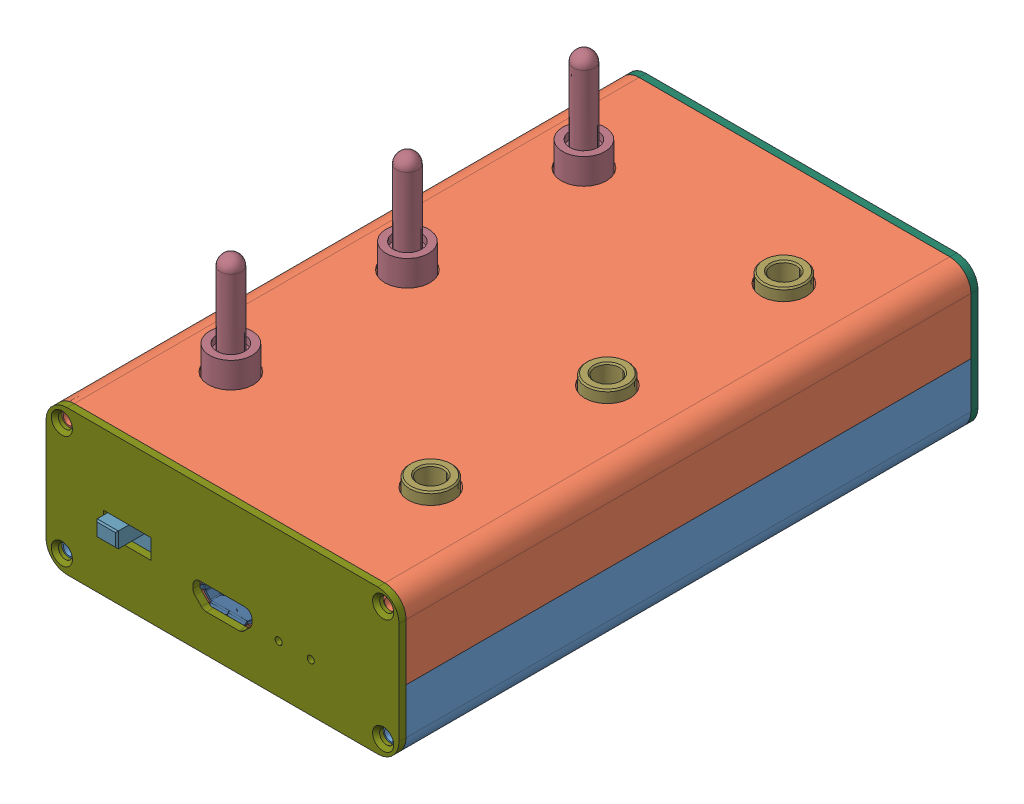
SolidWorks assembly case-full, configuration Default. Lengths in mm.
Overall size (50 35 83.41).
112 component instances, 26 part files, 14 mates.
Components (placement in the parent):
- case-1: case [Default] at (-9.9049 -10.2865 -40) size (50 11 80)
- top-case-2: top-case [Default] at (1.6835 8.41 -40) x (-1 0 0) z (0 0 1) size (50 11 80)
- PCB-assembly-1: PCB-assembly [Default] at (-5.9703 -42.4723 -73.1659) x (0 0 -1) z (0 1 0) size (82.41 47 32.65)
  - ledTruck_PCB.step-1: ledTruck_PCB.step [Default] at (-218.1999 94.1524 35.3841) size (80.38 47 12.68)
    - ledTruck.step-1: ledTruck.step [Default] at origin size (80.38 47 12.68)
      - R_0603_1608Metric.step-1: R_0603_1608Metric.step [Default] at (162.2298 -104.8258 1.65) size (1.6 0.8 0.45)
        - SOLID.step-1: SOLID.step [Default] at origin size (1.6 0.8 0.45)
      - SOT-23-5.step-1: SOT-23-5.step [Default] at (130.302 -76.708 1.65) x (0 -1 0) z (0 0 1) size (2.8 2.9 1.55)
        - SOLID-0.step-1: SOLID-0.step [Default] at origin size (2.8 2.9 1.55)
      - SOT-23-5.step-2: SOT-23-5.step [Default] at (137.16 -76.708 1.65) x (0 -1 0) z (0 0 1) size (2.8 2.9 1.55)
        - SOLID-0.step-1: SOLID-0.step [Default] at origin size (2.8 2.9 1.55)
      - R_0603_1608Metric.step-2: R_0603_1608Metric.step [Default] at (162.433 -79.248 1.65) size (1.6 0.8 0.45)
        - SOLID.step-1: SOLID.step [Default] at origin size (1.6 0.8 0.45)
      - R_0603_1608Metric.step-3: R_0603_1608Metric.step [Default] at (162.433 -76.835 1.65) x (-1 0 0) z (0 0 1) size (1.6 0.8 0.45)
        - SOLID.step-1: SOLID.step [Default] at origin size (1.6 0.8 0.45)
      - R_0603_1608Metric.step-4: R_0603_1608Metric.step [Default] at (108.1929 -114.012 1.65) size (1.6 0.8 0.45)
        - SOLID.step-1: SOLID.step [Default] at origin size (1.6 0.8 0.45)
      - R_0603_1608Metric.step-5: R_0603_1608Metric.step [Default] at (108.1929 -115.512 1.65) size (1.6 0.8 0.45)
        - SOLID.step-1: SOLID.step [Default] at origin size (1.6 0.8 0.45)
      - R_0603_1608Metric.step-6: R_0603_1608Metric.step [Default] at (152.146 -80.01 1.65) size (1.6 0.8 0.45)
        - SOLID.step-1: SOLID.step [Default] at origin size (1.6 0.8 0.45)
      - R_0603_1608Metric.step-7: R_0603_1608Metric.step [Default] at (165.1 -84.836 1.65) x (0 1 0) z (0 0 1) size (1.6 0.8 0.45)
        - SOLID.step-1: SOLID.step [Default] at origin size (1.6 0.8 0.45)
      - R_0603_1608Metric.step-8: R_0603_1608Metric.step [Default] at (137.16 -80.264 1.65) x (-1 0 0) z (0 0 1) size (1.6 0.8 0.45)
        - SOLID.step-1: SOLID.step [Default] at origin size (1.6 0.8 0.45)
      - R_0603_1608Metric.step-9: R_0603_1608Metric.step [Default] at (156.972 -111.506 1.65) x (-1 0 0) z (0 0 1) size (1.6 0.8 0.45)
        - SOLID.step-1: SOLID.step [Default] at origin size (1.6 0.8 0.45)
      - R_0603_1608Metric.step-10: R_0603_1608Metric.step [Default] at (156.972 -107.442 1.65) size (1.6 0.8 0.45)
        - SOLID.step-1: SOLID.step [Default] at origin size (1.6 0.8 0.45)
      - R_0603_1608Metric.step-11: R_0603_1608Metric.step [Default] at (132.842 -113.284 1.65) size (1.6 0.8 0.45)
        - SOLID.step-1: SOLID.step [Default] at origin size (1.6 0.8 0.45)
      - R_0603_1608Metric.step-12: R_0603_1608Metric.step [Default] at (156.972 -109.474 1.65) x (-1 0 0) z (0 0 1) size (1.6 0.8 0.45)
        - SOLID.step-1: SOLID.step [Default] at origin size (1.6 0.8 0.45)
      - R_0603_1608Metric.step-13: R_0603_1608Metric.step [Default] at (156.972 -105.283 1.65) x (-1 0 0) z (0 0 1) size (1.6 0.8 0.45)
        - SOLID.step-1: SOLID.step [Default] at origin size (1.6 0.8 0.45)
      - R_0603_1608Metric.step-14: R_0603_1608Metric.step [Default] at (132.828 -111.379 1.65) size (1.6 0.8 0.45)
        - SOLID.step-1: SOLID.step [Default] at origin size (1.6 0.8 0.45)
      - L_0805_2012Metric.step-1: L_0805_2012Metric.step [Default] at (130.336 -80.264 1.65) x (-1 0 0) z (0 0 1) size (2 1.25 1.25)
        - SOLID-1.step-1: SOLID-1.step [Default] at origin size (2 1.25 1.25)
      - C_0805_2012Metric.step-1: C_0805_2012Metric.step [Default] at (130.302 -87.122 1.65) size (2 1.25 1.25)
        - SOLID-2.step-1: SOLID-2.step [Default] at origin size (2 1.25 1.25)
      - C_0603_1608Metric.step-1: C_0603_1608Metric.step [Default] at (152.146 -78.486 1.65) x (-1 0 0) z (0 0 1) size (1.6 0.8 0.8)
        - SOLID-3.step-1: SOLID-3.step [Default] at origin size (1.6 0.8 0.8)
      - C_0805_2012Metric.step-2: C_0805_2012Metric.step [Default] at (137.16 -83.566 1.65) size (2 1.25 1.25)
        - SOLID-2.step-1: SOLID-2.step [Default] at origin size (2 1.25 1.25)
      - C_0603_1608Metric.step-2: C_0603_1608Metric.step [Default] at (152.146 -76.962 1.65) x (-1 0 0) z (0 0 1) size (1.6 0.8 0.8)
        - SOLID-3.step-1: SOLID-3.step [Default] at origin size (1.6 0.8 0.8)
      - C_0603_1608Metric.step-3: C_0603_1608Metric.step [Default] at (152.146 -75.464 1.65) x (-1 0 0) z (0 0 1) size (1.6 0.8 0.8)
        - SOLID-3.step-1: SOLID-3.step [Default] at origin size (1.6 0.8 0.8)
      - C_0805_2012Metric.step-3: C_0805_2012Metric.step [Default] at (130.302 -83.566 1.65) size (2 1.25 1.25)
        - SOLID-2.step-1: SOLID-2.step [Default] at origin size (2 1.25 1.25)
      - C_0603_1608Metric.step-4: C_0603_1608Metric.step [Default] at (162.56 -81.534 1.65) size (1.6 0.8 0.8)
        - SOLID-3.step-1: SOLID-3.step [Default] at origin size (1.6 0.8 0.8)
      - C_0603_1608Metric.step-5: C_0603_1608Metric.step [Default] at (162.56 -88.138 1.65) size (1.6 0.8 0.8)
        - SOLID-3.step-1: SOLID-3.step [Default] at origin size (1.6 0.8 0.8)
      - C_0805_2012Metric.step-4: C_0805_2012Metric.step [Default] at (137.16 -87.122 1.65) size (2 1.25 1.25)
        - SOLID-2.step-1: SOLID-2.step [Default] at origin size (2 1.25 1.25)
      - R_0603_1608Metric.step-15: R_0603_1608Metric.step [Default] at (125.984 -75.946 1.65) size (1.6 0.8 0.45)
        - SOLID.step-1: SOLID.step [Default] at origin size (1.6 0.8 0.45)
      - R_0603_1608Metric.step-16: R_0603_1608Metric.step [Default] at (114.046 -80.264 1.65) x (0 -1 0) z (0 0 1) size (1.6 0.8 0.45)
        - SOLID.step-1: SOLID.step [Default] at origin size (1.6 0.8 0.45)
      - LED_0805_2012Metric.step-1: LED_0805_2012Metric.step [Default] at (107.6929 -108.512 1.65) x (0 -1 0) z (0 0 1) size (2 1.25 1.1)
        - SOLID-4.step-1: SOLID-4.step [Default] at origin size (2 1.25 1.1)
      - LED_0805_2012Metric.step-2: LED_0805_2012Metric.step [Default] at (107.6929 -103.962 1.65) x (0 -1 0) z (0 0 1) size (2 1.25 1.1)
        - SOLID-4.step-1: SOLID-4.step [Default] at origin size (2 1.25 1.1)
      - C_0603_1608Metric.step-6: C_0603_1608Metric.step [Default] at (125.984 -77.978 1.65) x (-1 0 0) z (0 0 1) size (1.6 0.8 0.8)
        - SOLID-3.step-1: SOLID-3.step [Default] at origin size (1.6 0.8 0.8)
      - SW_CuK_JS202011AQN_DPDT_Angled.step-1: SW_CuK_JS202011AQN_DPDT_Angled.step [Default] at (111.474 -79.012 1.65) x (0 -1 0) z (0 0 1) size (9 5.6 6.5) (hidden)
        - SOLID-5.step-1: SOLID-5.step [Default] at origin size (9 5.6 6.5)
      - JST_XH_S2B-XH-A_1x02_P2.50mm_Horizontal.step-1: JST_XH_S2B-XH-A_1x02_P2.50mm_Horizontal.step [Default] at (179.578 -78.012 1.65) size (7.4 11.5 9.5)
        - SOLID-6.step-1: SOLID-6.step [Default] at origin size (7.4 11.5 9.5)
      - USB_Micro-B_Molex_47346-0001.step-1: USB_Micro-B_Molex_47346-0001.step [Default] at (108.4213 -96.0044 1.65) x (0 -1 0) z (0 0 1) size (7.98 5.42 2.94)
        - SOLID-7.step-1: SOLID-7.step [Default] at origin size (7.98 5.42 2.94)
      - Crystal_SMD_0603-4Pin_6.0x3.5mm.step-1: Crystal_SMD_0603-4Pin_6.0x3.5mm.step [Default] at (162.56 -84.856 1.65) x (0 1 0) z (0 0 1) size (6 3.5 1.03)
        - SOLID-8.step-1: SOLID-8.step [Default] at origin size (6 3.5 1.03) (hidden)
      - 7101 ToggleSwitch.step-1: 7101 ToggleSwitch.step [Default] at (121.534 -82.012 10.15) size (0.36 0.5 1.28) (hidden)
        - SOLID-9.step-1: SOLID-9.step [Default] at origin size (0.28 0.5 0.35) (hidden)
        - SOLID-10.step-1: SOLID-10.step [Default] at origin size (0.24 0.24 0.35)
        - SOLID-11.step-1: SOLID-11.step [Default] at origin size (0.12 0.21 0.43)
        - SOLID-12.step-1: SOLID-12.step [Default] at origin size (0.36 0.31 0.06)
        - SOLID-13.step-1: SOLID-13.step [Default] at origin size (0.36 0.31 0.06)
        - SOLID-14.step-1: SOLID-14.step [Default] at origin size (0.08 0.03 0.16)
        - SOLID-15.step-1: SOLID-15.step [Default] at origin size (0.08 0.03 0.16)
        - SOLID-16.step-1: SOLID-16.step [Default] at origin size (0.08 0.03 0.16)
      - 7101 ToggleSwitch.step-2: 7101 ToggleSwitch.step [Default] at (146.534 -82.012 10.15) size (0.36 0.5 1.28) (hidden)
        - SOLID-9.step-1: SOLID-9.step [Default] at origin size (0.28 0.5 0.35) (hidden)
        - SOLID-10.step-1: SOLID-10.step [Default] at origin size (0.24 0.24 0.35)
        - SOLID-11.step-1: SOLID-11.step [Default] at origin size (0.12 0.21 0.43)
        - SOLID-12.step-1: SOLID-12.step [Default] at origin size (0.36 0.31 0.06)
        - SOLID-13.step-1: SOLID-13.step [Default] at origin size (0.36 0.31 0.06)
        - SOLID-14.step-1: SOLID-14.step [Default] at origin size (0.08 0.03 0.16)
        - SOLID-15.step-1: SOLID-15.step [Default] at origin size (0.08 0.03 0.16)
        - SOLID-16.step-1: SOLID-16.step [Default] at origin size (0.08 0.03 0.16)
      - 7101 ToggleSwitch.step-3: 7101 ToggleSwitch.step [Default] at (171.534 -82.012 10.15) size (0.36 0.5 1.28) (hidden)
        - SOLID-9.step-1: SOLID-9.step [Default] at origin size (0.28 0.5 0.35) (hidden)
        - SOLID-10.step-1: SOLID-10.step [Default] at origin size (0.24 0.24 0.35)
        - SOLID-11.step-1: SOLID-11.step [Default] at origin size (0.12 0.21 0.43)
        - SOLID-12.step-1: SOLID-12.step [Default] at origin size (0.36 0.31 0.06)
        - SOLID-13.step-1: SOLID-13.step [Default] at origin size (0.36 0.31 0.06)
        - SOLID-14.step-1: SOLID-14.step [Default] at origin size (0.08 0.03 0.16)
        - SOLID-15.step-1: SOLID-15.step [Default] at origin size (0.08 0.03 0.16)
        - SOLID-16.step-1: SOLID-16.step [Default] at origin size (0.08 0.03 0.16)
      - COMPOUND.step-1: COMPOUND.step [Default] at origin size (80 47 1.6)
  - 3,5mmjack-1: 3,5mmjack [Default] at (-98.1659 -15.3596 36.9841) size (8 8 18.3)
  - 3,5mmjack-2: 3,5mmjack [Default] at (-73.1659 -15.3596 36.9841) size (8 8 18.3)
  - 3,5mmjack-3: 3,5mmjack [Default] at (-48.1659 -15.3596 36.9841) size (8 8 18.3)
  - toggle-switch-2: toggle-switch [Default] at (-47.8013 13.9041 36.9841) x (1 0 0) z (0 -1 0) size (6.9 31.5 13.2)
  - toggle-switch-3: toggle-switch [Default] at (-72.8013 13.9041 36.9841) x (1 0 0) z (0 -1 0) size (6.9 31.5 13.2)
  - toggle-switch-4: toggle-switch [Default] at (-97.8013 13.9041 36.9841) x (1 0 0) z (0 -1 0) size (6.9 31.5 13.2)
  - slideswitch-1: slideswitch [Default] at (-109.6165 12.0841 36.9841) x (0 -1 0) z (-1 0 0) size (13 8.2 9.7)
- case-lid-1: case-lid [Default] at (-11.7051 -0.4225 -41) size (50 20.5 1)
- case-lid-usb-1: case-lid-usb [Default] at (-11.7051 -0.4225 40) size (50 20.5 1)
Mates (geometry in assembly coordinates):
- Coincident1: coincident aligned: plane of case-1 through (-27.6107 -2.4882 40) normal (1 0 0); plane of case-2 through (-27.6107 2.6118 40) normal (1 0 0)
- Coincident3: coincident aligned: plane of case-1 through (-27.6107 -2.4882 40) normal (1 0 0); plane of case-2 through (-27.6107 2.6118 40) normal (1 0 0)
- Parallel2: parallel aligned: plane of case-1 through (19.3893 -4.4882 40) normal (-1 0 0); plane of case-2 through (19.3893 0.6118 40) normal (-1 0 0)
- Coincident6: coincident anti-aligned: plane of case-1 through (19.8933 -1.6882 40) normal (0 1 0); plane of case-2 through (20.8893 -1.6882 40) normal (0 -1 0)
- Coincident7: coincident aligned: plane of case-1 through (-26.1107 -8.1882 40) normal (0 0 1); plane of case-2 through (17.8893 6.3118 40) normal (0 0 1)
- Coincident9: coincident anti-aligned: plane of case-1 through (-27.6107 -5.4882 40) normal (1 0 0); plane of PCB-assembly-1/ledTruck_PCB.step-1/ledTruck.step-1/COMPOUND.step-1 through (-27.6107 -7.0882 40) normal (-1 0 0)
- Coincident10: coincident anti-aligned: plane of case-1 through (19.3893 -5.4882 40) normal (0 -1 0); plane of PCB-assembly-1/ledTruck_PCB.step-1/ledTruck.step-1/COMPOUND.step-1 through (-4.1107 -5.4882 0) normal (0 1 0)
- Coincident11: coincident aligned: plane of case-1 through (-26.1107 -8.1882 40) normal (0 0 1); plane of PCB-assembly-1/ledTruck_PCB.step-1/ledTruck.step-1/COMPOUND.step-1 through (19.3893 -7.0882 40) normal (0 0 1)
- Coincident12: coincident anti-aligned: plane of case-2 through (17.8893 6.3118 -40) normal (0 0 -1); plane of case-lid-1 through (17.8893 6.3118 -40) normal (0 0 1)
- Coincident13: coincident aligned: plane of case-2 through (17.8893 9.3118 40) normal (0 1 0); plane of case-lid-1 through (-26.1107 9.3118 -40) normal (0 1 0)
- Coincident14: coincident aligned: plane of case-1 through (-29.1107 -0.1882 40) normal (-1 0 0); plane of case-lid-1 through (-29.1107 6.3118 -40) normal (-1 0 0)
- Coincident15: coincident anti-aligned: plane of case-2 through (17.8893 6.3118 40) normal (0 0 1); plane of case-lid-usb-1 through (17.8893 6.3118 40) normal (0 0 -1)
- Coincident16: coincident aligned: plane of case-2 through (17.8893 9.3118 40) normal (0 1 0); plane of case-lid-usb-1 through (-26.1107 9.3118 41) normal (0 1 0)
- Coincident18: coincident aligned: plane of case-2 through (-29.1107 6.3118 40) normal (-1 0 0); plane of case-lid-usb-1 through (-29.1107 6.3118 41) normal (-1 0 0)
